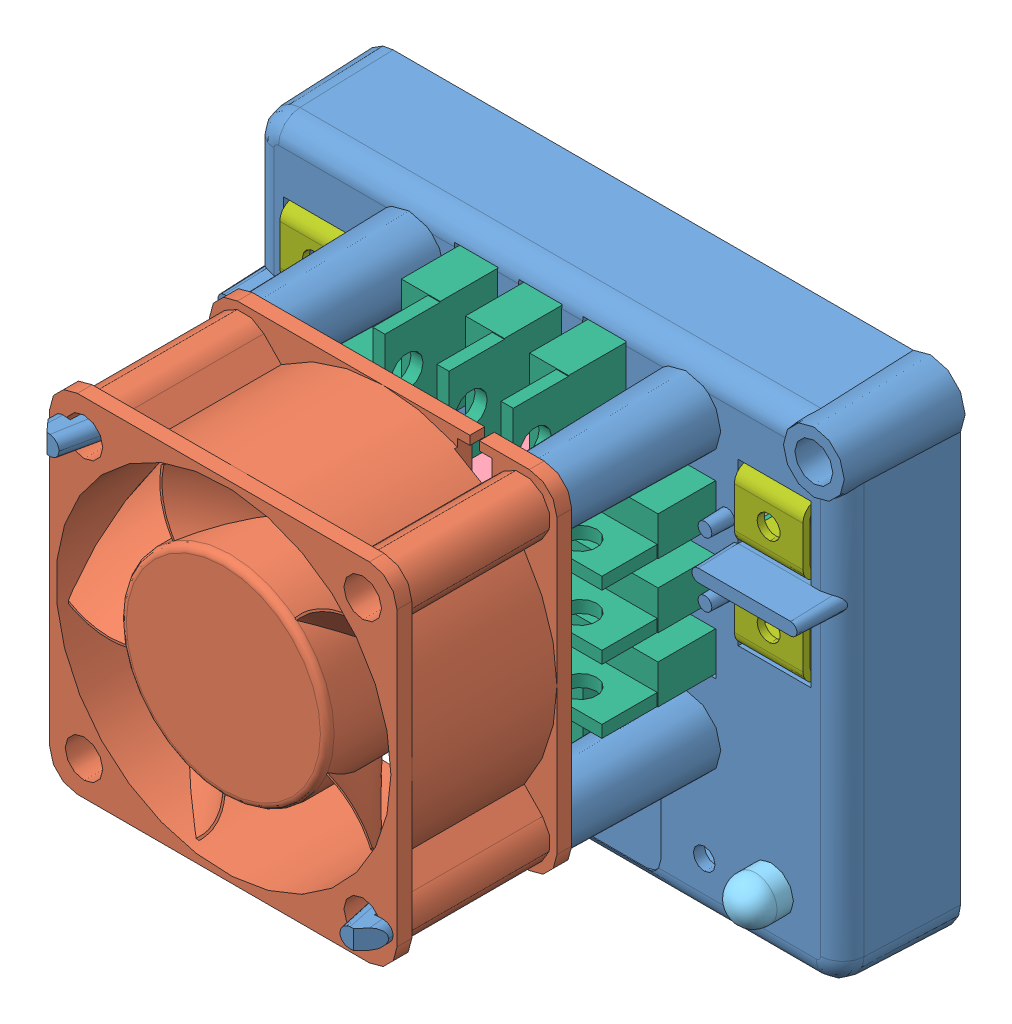
SolidWorks assembly Victor884, configuration Default. Lengths in mm.
Overall size (69.65 56.95 53.28).
22 component instances, 8 part files, 0 mates.
Components (placement in the parent):
- Victor884-Cover-1: Victor884-Cover [Default] at origin size (69.65 56.95 53.28)
- Fan-PAPST-412-1: Fan-PAPST-412 [Default] at (-18.7322 -1.3534 40.2082) x (1 0 0) z (0 0 -1) size (39.88 39.88 20.07)
- Victor884-Base-1: Victor884-Base [Default] at (6.7866 -24.0693 0.127) size (66.29 53.59 9.91)
- Victor884-Capacitor-1: Victor884-Capacitor [Default] at (-18.6052 -1.2264 18.3642) x (0.989031 0.147708 0) z (0 0 1) size (12.7 12.7 20.33)
- Victor884-LED - Green-1: Victor884-LED - Green [Default] at (7.0869 -27.9091 8.7012) x (0.893703 -0.448659 0) z (-0.448659 -0.893703 0) size (5.9 9 5.9)
- Victor884-Fet-1: Victor884-Fet [Default] at (-12.6489 -15.1964 10.8712) x (0 1 0) z (1 0 0) size (10.16 22.61 4.47)
- Victor884-Fet-2: Victor884-Fet [Default] at (-20.0149 -15.1964 10.8712) x (0 1 0) z (1 0 0) size (10.16 22.61 4.47)
- Victor884-Fet-3: Victor884-Fet [Default] at (-27.3809 -15.1964 10.8712) x (0 1 0) z (1 0 0) size (10.16 22.61 4.47)
- Victor884-Fet-4: Victor884-Fet [Default] at (-4.6352 4.7299 10.8712) x (-1 0 0) z (0 1 0) size (10.16 22.61 4.47)
- Victor884-Fet-5: Victor884-Fet [Default] at (-4.6352 -2.6361 10.8712) x (-1 0 0) z (0 1 0) size (10.16 22.61 4.47)
- Victor884-Fet-6: Victor884-Fet [Default] at (-4.6352 -10.0021 10.8712) x (-1 0 0) z (0 1 0) size (10.16 22.61 4.47)
- Victor884-Fet-7: Victor884-Fet [Default] at (-24.5615 12.7436 10.8712) x (0 -1 0) z (-1 0 0) size (10.16 22.61 4.47)
- Victor884-Fet-8: Victor884-Fet [Default] at (-17.1955 12.7436 10.8712) x (0 -1 0) z (-1 0 0) size (10.16 22.61 4.47)
- Victor884-Fet-9: Victor884-Fet [Default] at (-9.8295 12.7436 10.8712) x (0 -1 0) z (-1 0 0) size (10.16 22.61 4.47)
- Victor884-Fet-10: Victor884-Fet [Default] at (-32.5752 -7.1827 10.8712) x (1 0 0) z (0 -1 0) size (10.16 22.61 4.47)
- Victor884-Fet-11: Victor884-Fet [Default] at (-32.5752 0.1833 10.8712) x (1 0 0) z (0 -1 0) size (10.16 22.61 4.47)
- Victor884-Fet-12: Victor884-Fet [Default] at (-32.5752 7.5493 10.8712) x (1 0 0) z (0 -1 0) size (10.16 22.61 4.47)
- Victor884 Screw Terminal-1: Victor884 Screw Terminal [Default] at (-48.5772 12.6166 13.9192) x (1 0 0) z (0 0 -1) size (7.87 7.87 10.34)
- Victor884 Screw Terminal-2: Victor884 Screw Terminal [Default] at (-48.5772 2.4566 13.9192) x (1 0 0) z (0 0 -1) size (7.87 7.87 10.34)
- Victor884 Screw Terminal-3: Victor884 Screw Terminal [Default] at (3.6198 12.6166 13.9192) x (1 0 0) z (0 0 -1) size (7.87 7.87 10.34)
- Victor884 Screw Terminal-4: Victor884 Screw Terminal [Default] at (3.6198 2.4566 13.9192) x (1 0 0) z (0 0 -1) size (7.87 7.87 10.34)
- Victor884-3 Pin Connector-1: Victor884-3 Pin Connector [Default] at (-48.3232 -24.0229 8.3312) x (0 -1 0) z (0 0 1) size (2.54 7.62 11.43)
